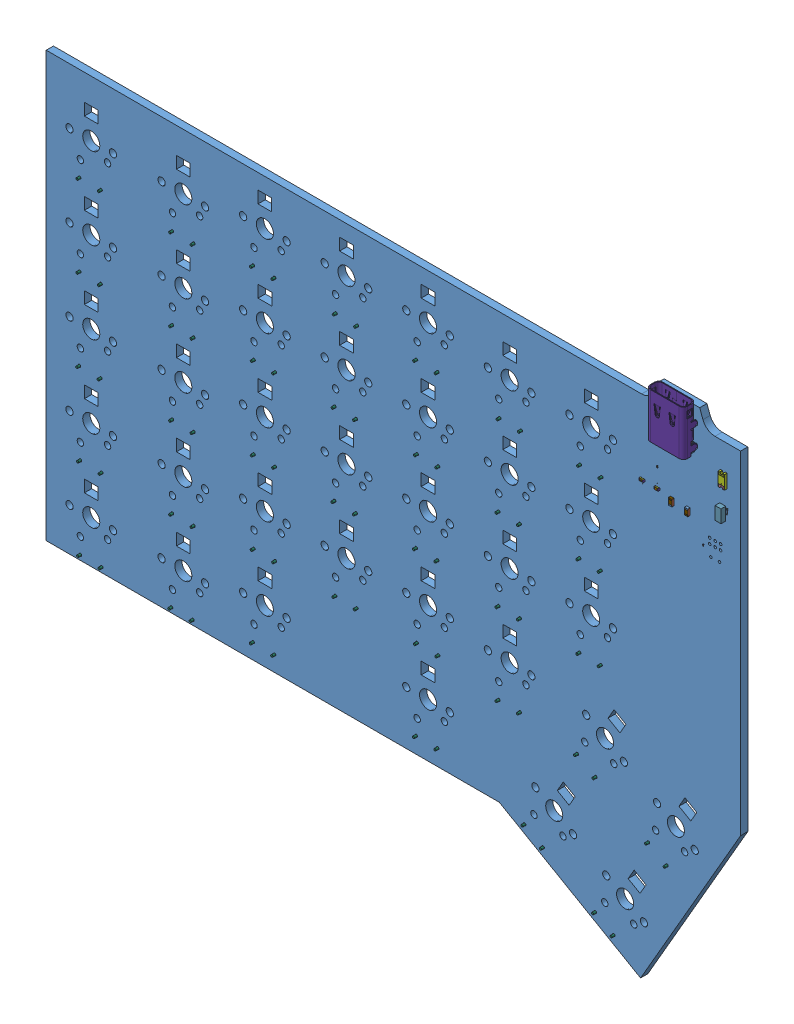
SolidWorks assembly WIRED_PCB, configuration Default. Lengths in mm.
Overall size (162.15 123.21 6.5).
313 component instances, 99 part files, 0 mates.
Components (placement in the parent):
- Board-1: Board [Default] at origin size (162.15 122.24 1.69)
  - Open CASCADE STEP translator 6.8 2.1.1-1: Open CASCADE STEP translator 6.8 2.1.1 [Default] at (0 0 -1.6914) size (162.15 122.24 1.69)
- X1-1: X1 [Default] at origin size (5 3.2 1.05)
  - 5613965808-1: 5613965808 [Default] at (149.15 67.35 -2.7414) size (5 3.2 1.05)
    - Extruded_10-1: Extruded_10 [Default] at origin size (5 3.2 1.05)
- ATmega32U4-1: ATmega32U4 [Default] at origin size (10 10 1.2)
  - 7433191200-1: 7433191200 [Default] at (148.8 79.4 -2.8914) size (10 10 1.2)
    - Extruded_5-1: Extruded_5 [Default] at origin size (10 10 1.2)
- R6-1: R6 [Default] at origin size (1.7 0.95 0.55)
  - 7434017360-1: 7434017360 [Default] at (141 90 -1.6914) x (1 0 0) z (0 0 -1) size (1.7 0.95 0.55)
    - Mid_Body-1: Mid_Body [Default] at (-0.85 -0.475 0) size (1.59 0.95 0.44)
    - Terminal-1: Terminal [Default] at (-0.85 -0.475 0) size (0.1 0.95 0.55)
      - Open_CASCADE_STEP_translator_6.8_1.2.1-1: Open_CASCADE_STEP_translator_6.8_1.2.1 [Default] at origin size (0.1 0.95 0.55)
    - Terminal-2: Terminal [Default] at (0.85 0.475 0) x (-1 0 0) z (0 0 1) size (0.1 0.95 0.55)
      - Open_CASCADE_STEP_translator_6.8_1.2.1-1: Open_CASCADE_STEP_translator_6.8_1.2.1 [Default] at origin size (0.1 0.95 0.55)
    - Mark-1: Mark [Default] at (-0.75 -0.475 0.495) size (1.5 0.95 0.06)
- R5-1: R5 [Default] at origin size (1 1.18 0.41)
  - Res_Vishay_CRCW04021K00FKED_eec-1: Res_Vishay_CRCW04021K00FKED_eec [Default] at (139.2978 111 0) x (-1 0 0) z (0 0 1) size (1 1.18 0.41)
    - body-1: body [Default] at (0 0 0.35) x (1 0 0) z (0 0 -1) size (0.9 0.5 0.3)
    - pad_2-1: pad_2 [Default] at (-0.3133 -0.25 0.4) x (1 0 0) z (0 1 0) size (0.25 0.4 0.5)
    - pad_2-2: pad_2 [Default] at (0.3133 0.25 0.4) x (-1 0 0) z (0 -1 0) size (0.25 0.4 0.5)
    - top-1: top [Default] at (0 0 0.4) x (1 0 0) z (0 0 -1) size (0.61 0.51 0.06)
    - Vishay_3-1: Vishay_3 [Default] at (0.0437 -0.9162 0.4) size (0.15 0.04 0)
    - Vishay_2-1: Vishay_2 [Default] at (0 -0.0009 0.0004) size (0.07 0.06 0)
    - Vishay_7-1: Vishay_7 [Default] at origin size (0.03 0.03 0)
    - Vishay-1: Vishay [Default] at origin size (0.01 0.03 0)
    - Vishay_6-1: Vishay_6 [Default] at origin size (0.03 0.03 0)
    - Vishay_8-1: Vishay_8 [Default] at origin size (0.03 0.03 0)
    - Vishay_5-1: Vishay_5 [Default] at origin size (0.03 0.03 0)
    - Vishay_4-1: Vishay_4 [Default] at origin size (0.03 0.03 0)
- R4-1: R4 [Default] at origin size (1 1.18 0.41)
  - Res_Vishay_CRCW04021K00FKED_eec-1: Res_Vishay_CRCW04021K00FKED_eec [Default] at (142.7978 111 0) size (1 1.18 0.41)
    - body-1: body [Default] at (0 0 0.35) x (1 0 0) z (0 0 -1) size (0.9 0.5 0.3)
    - pad_2-1: pad_2 [Default] at (-0.3133 -0.25 0.4) x (1 0 0) z (0 1 0) size (0.25 0.4 0.5)
    - pad_2-2: pad_2 [Default] at (0.3133 0.25 0.4) x (-1 0 0) z (0 -1 0) size (0.25 0.4 0.5)
    - top-1: top [Default] at (0 0 0.4) x (1 0 0) z (0 0 -1) size (0.61 0.51 0.06)
    - Vishay_3-1: Vishay_3 [Default] at (0.0437 -0.9162 0.4) size (0.15 0.04 0)
    - Vishay_2-1: Vishay_2 [Default] at (0 -0.0009 0.0004) size (0.07 0.06 0)
    - Vishay_7-1: Vishay_7 [Default] at origin size (0.03 0.03 0)
    - Vishay-1: Vishay [Default] at origin size (0.01 0.03 0)
    - Vishay_6-1: Vishay_6 [Default] at origin size (0.03 0.03 0)
    - Vishay_8-1: Vishay_8 [Default] at origin size (0.03 0.03 0)
    - Vishay_5-1: Vishay_5 [Default] at origin size (0.03 0.03 0)
    - Vishay_4-1: Vishay_4 [Default] at origin size (0.03 0.03 0)
- R3-1: R3 [Default] at origin size (3.98 6.22 0.56)
  - Res_TE_Connectivity_CPF0603B2K55E1_eec-1: Res_TE_Connectivity_CPF0603B2K55E1_eec [Default] at (146.25 110.1 0) x (0 -1 0) z (0 0 1) size (6.22 3.98 0.56)
    - 1_2-1: 1_2 [Default] at origin size (0.3 0.8 0.55)
    - 1-1: 1 [Default] at origin size (0.3 0.8 0.55)
    - 2-1: 2 [Default] at origin size (1.45 0.8 0.5)
    - TE_connectivity_Logo_1_11-1: TE_connectivity_Logo_1_11 [Default] at (5.0457 3.7568 0.451) x (-1 0 0) z (0 0 1) size (0.01 0.03 0.1)
    - TE_connectivity_Logo_1_10-1: TE_connectivity_Logo_1_10 [Default] at (0.005 0.0038 0.0005) x (-1 0 0) z (0 0 1) size (0.01 0.03 0.1)
    - TE_connectivity_Logo_1_9-1: TE_connectivity_Logo_1_9 [Default] x (-1 0 0) z (0 0 1) size (0.02 0.02 0.1)
    - TE_connectivity_Logo_1_8-1: TE_connectivity_Logo_1_8 [Default] x (-1 0 0) z (0 0 1) size (0.02 0.02 0.1)
    - TE_connectivity_Logo_1_2-1: TE_connectivity_Logo_1_2 [Default] x (-1 0 0) z (0 0 1) size (0.02 0.02 0.1)
    - TE_connectivity_Logo_1_12-1: TE_connectivity_Logo_1_12 [Default] x (-1 0 0) z (0 0 1) size (0.11 0.12 0.1)
    - TE_connectivity_Logo_1_5-1: TE_connectivity_Logo_1_5 [Default] x (-1 0 0) z (0 0 1) size (0.16 0.04 0.1)
    - TE_connectivity_Logo_1_7-1: TE_connectivity_Logo_1_7 [Default] x (-1 0 0) z (0 0 1) size (0.16 0.04 0.1)
    - TE_connectivity_Logo_1-1: TE_connectivity_Logo_1 [Default] x (-1 0 0) z (0 0 1) size (0.16 0.04 0.1)
    - TE_connectivity_Logo_1_14-1: TE_connectivity_Logo_1_14 [Default] x (-1 0 0) z (0 0 1) size (0.1 0.12 0.1)
    - TE_connectivity_Logo_1_6-1: TE_connectivity_Logo_1_6 [Default] x (-1 0 0) z (0 0 1) size (0.02 0.03 0.1)
    - TE_connectivity_Logo_1_3-1: TE_connectivity_Logo_1_3 [Default] x (-1 0 0) z (0 0 1) size (0.02 0.02 0.1)
    - TE_connectivity_Logo_1_13-1: TE_connectivity_Logo_1_13 [Default] x (-1 0 0) z (0 0 1) size (0.02 0.02 0.11)
    - TE_connectivity_Logo_1_4-1: TE_connectivity_Logo_1_4 [Default] x (-1 0 0) z (0 0 1) size (0.02 0.02 0.1)
    - TE_connectivity_Logo_1_15-1: TE_connectivity_Logo_1_15 [Default] x (-1 0 0) z (0 0 1) size (0.02 0.03 0.1)
    - 3-1: 3 [Default] at origin size (0.95 0.8 0.05)
- R2-1: R2 [Default] at origin size (3.98 6.22 0.56)
  - Res_TE_Connectivity_CPF0603B2K55E1_eec-1: Res_TE_Connectivity_CPF0603B2K55E1_eec [Default] at (150 110 0) x (0 1 0) z (0 0 1) size (6.22 3.98 0.56)
    - 1_2-1: 1_2 [Default] at origin size (0.3 0.8 0.55)
    - 1-1: 1 [Default] at origin size (0.3 0.8 0.55)
    - 2-1: 2 [Default] at origin size (1.45 0.8 0.5)
    - TE_connectivity_Logo_1_11-1: TE_connectivity_Logo_1_11 [Default] at (5.0457 3.7568 0.451) x (-1 0 0) z (0 0 1) size (0.01 0.03 0.1)
    - TE_connectivity_Logo_1_10-1: TE_connectivity_Logo_1_10 [Default] at (0.005 0.0038 0.0005) x (-1 0 0) z (0 0 1) size (0.01 0.03 0.1)
    - TE_connectivity_Logo_1_9-1: TE_connectivity_Logo_1_9 [Default] x (-1 0 0) z (0 0 1) size (0.02 0.02 0.1)
    - TE_connectivity_Logo_1_8-1: TE_connectivity_Logo_1_8 [Default] x (-1 0 0) z (0 0 1) size (0.02 0.02 0.1)
    - TE_connectivity_Logo_1_2-1: TE_connectivity_Logo_1_2 [Default] x (-1 0 0) z (0 0 1) size (0.02 0.02 0.1)
    - TE_connectivity_Logo_1_12-1: TE_connectivity_Logo_1_12 [Default] x (-1 0 0) z (0 0 1) size (0.11 0.12 0.1)
    - TE_connectivity_Logo_1_5-1: TE_connectivity_Logo_1_5 [Default] x (-1 0 0) z (0 0 1) size (0.16 0.04 0.1)
    - TE_connectivity_Logo_1_7-1: TE_connectivity_Logo_1_7 [Default] x (-1 0 0) z (0 0 1) size (0.16 0.04 0.1)
    - TE_connectivity_Logo_1-1: TE_connectivity_Logo_1 [Default] x (-1 0 0) z (0 0 1) size (0.16 0.04 0.1)
    - TE_connectivity_Logo_1_14-1: TE_connectivity_Logo_1_14 [Default] x (-1 0 0) z (0 0 1) size (0.1 0.12 0.1)
    - TE_connectivity_Logo_1_6-1: TE_connectivity_Logo_1_6 [Default] x (-1 0 0) z (0 0 1) size (0.02 0.03 0.1)
    - TE_connectivity_Logo_1_3-1: TE_connectivity_Logo_1_3 [Default] x (-1 0 0) z (0 0 1) size (0.02 0.02 0.1)
    - TE_connectivity_Logo_1_13-1: TE_connectivity_Logo_1_13 [Default] x (-1 0 0) z (0 0 1) size (0.02 0.02 0.11)
    - TE_connectivity_Logo_1_4-1: TE_connectivity_Logo_1_4 [Default] x (-1 0 0) z (0 0 1) size (0.02 0.02 0.1)
    - TE_connectivity_Logo_1_15-1: TE_connectivity_Logo_1_15 [Default] x (-1 0 0) z (0 0 1) size (0.02 0.03 0.1)
    - 3-1: 3 [Default] at origin size (0.95 0.8 0.05)
- R1-1: R1 [Default] at origin size (1.66 3.2 0.66)
  - Res_Vishay_MCA12060D1541BP100_eec-1: Res_Vishay_MCA12060D1541BP100_eec [Default] at (159.25 66 -1.6914) x (0 -1 0) z (0 0 -1) size (3.2 1.66 0.66)
    - body_3-1: body_3 [Default] at (0 0 0.6) x (1 0 0) z (0 0 -1) size (3.1 1.6 0.55)
    - pad-1: pad [Default] at (-1.4133 -0.8 0.65) x (1 0 0) z (0 1 0) size (0.5 0.65 1.6)
    - pad-2: pad [Default] at (1.4133 0.8 0.65) x (-1 0 0) z (0 -1 0) size (0.5 0.65 1.6)
    - top_2-1: top_2 [Default] at (0 0 0.65) x (1 0 0) z (0 0 -1) size (2.2 1.6 0.05)
    - Vishay_15-1: Vishay_15 [Default] at (0.0405 -0.7888 0.65) size (0.45 0.11 0.01)
    - Vishay_14-1: Vishay_14 [Default] at (0 -0.0008 0.0006) size (0.21 0.18 0.01)
    - Vishay_11-1: Vishay_11 [Default] at origin size (0.09 0.09 0.01)
    - Vishay_9-1: Vishay_9 [Default] at origin size (0.03 0.08 0.01)
    - Vishay_13-1: Vishay_13 [Default] at origin size (0.08 0.09 0.01)
    - Vishay_16-1: Vishay_16 [Default] at origin size (0.08 0.08 0.01)
    - Vishay_10-1: Vishay_10 [Default] at origin size (0.1 0.09 0.01)
    - Vishay_12-1: Vishay_12 [Default] at origin size (0.09 0.08 0.01)
    - bottom-1: bottom [Default] at (0 0 0.05) x (1 0 0) z (0 0 -1) size (2.2 1.6 0.05)
- J1-1: J1 [Default] at origin size (8.74 11.79 4.86)
  - 632723300011-1: 632723300011 [Default] at (147.4999 128.2749 1.57) x (1 0 0) z (0 1 0) size (8.74 4.86 11.79)
    - 632723300011_Housing-1: 632723300011_Housing [Default] at origin size (8.34 2.56 8.2)
    - 632723300011_Shielding_3_v3-1: 632723300011_Shielding_3_v3 [Default] at (0 0.05 0) size (7.5 3.43 8.64)
    - 632723300011_PIN2_Top_v3-1: 632723300011_PIN2_Top_v3 [Default] at (0.75 2.37 -6.335) x (0 0 1) z (0 -1 0) size (9.09 0.28 1.93)
    - 632723300011_Housing_TOP-1: 632723300011_Housing_TOP [Default] at (0 -0.6 -3.9) x (1 0 0) z (0 -1 0) size (6.7 3.25 1.23)
    - 632723300011_PIN2_Top_v3-2: 632723300011_PIN2_Top_v3 [Default] at (1.75 2.37 -6.335) x (0 0 1) z (0 -1 0) size (9.09 0.28 1.93)
    - 632723300011_PIN2_Top_v3-3: 632723300011_PIN2_Top_v3 [Default] at (2.25 2.37 -6.335) x (0 0 1) z (0 -1 0) size (9.09 0.28 1.93)
    - 632723300011_Shielding_1_v3-1: 632723300011_Shielding_1_v3 [Default] at (0 0 -0.475) x (-1 0 0) z (0 -1 0) size (8.74 10.6 4.86)
    - 632723300011_PIN1_Top_v3-1: 632723300011_PIN1_Top_v3 [Default] at (2.75 1.97 -6.335) x (0 0 1) z (0 -1 0) size (9.59 0.28 1.93)
    - 632723300011_PIN2_Top_v3-4: 632723300011_PIN2_Top_v3 [Default] at (-0.75 2.37 -6.335) x (0 0 1) z (0 -1 0) size (9.09 0.28 1.93)
    - 632723300011_PIN2_Top_v3-5: 632723300011_PIN2_Top_v3 [Default] at (-0.25 2.37 -6.335) x (0 0 1) z (0 -1 0) size (9.09 0.28 1.93)
    - 632723300011_PIN2_Top_v3-6: 632723300011_PIN2_Top_v3 [Default] at (-2.25 2.37 -6.335) x (0 0 1) z (0 -1 0) size (9.09 0.28 1.93)
    - 632723300011_PIN1_Top_v3-2: 632723300011_PIN1_Top_v3 [Default] at (-1.25 1.97 -6.335) x (0 0 1) z (0 -1 0) size (9.59 0.28 1.93)
    - 632723300011_PIN1_Top_v3-3: 632723300011_PIN1_Top_v3 [Default] at (-2.75 1.97 -6.335) x (0 0 1) z (0 -1 0) size (9.59 0.28 1.93)
    - 632723300011_PIN2_Top_v3-7: 632723300011_PIN2_Top_v3 [Default] at (-1.75 2.37 -6.335) x (0 0 1) z (0 -1 0) size (9.09 0.28 1.93)
    - 632723300011_Housing_Bottom-1: 632723300011_Housing_Bottom [Default] at (0 0.89 -5.285) x (-1 0 0) z (0 -1 0) size (8.34 5.47 2.38)
    - 632723300011_PIN1_Bottom_v3-1: 632723300011_PIN1_Bottom_v3 [Default] at (-2.8 3.3765 -5.46) x (1 0 0) z (0 -1 0) size (0.39 8.16 3.22)
    - 632723300011_PIN1_Top_v3-4: 632723300011_PIN1_Top_v3 [Default] at (1.25 1.97 -6.335) x (0 0 1) z (0 -1 0) size (9.59 0.28 1.93)
    - 632723300011_PIN2_Bottom_v3-1: 632723300011_PIN2_Bottom_v3 [Default] at (-2.4 3.3765 -4.75) x (1 0 0) z (0 -1 0) size (0.6 6.95 3.27)
    - 632723300011_PIN4_Bottom_v3-1: 632723300011_PIN4_Bottom_v3 [Default] at (-1.6 3.3765 -4.7565) x (1 0 0) z (0 -1 0) size (0.54 6.96 3.22)
    - 632723300011_PIN5_Bottom_v3-1: 632723300011_PIN5_Bottom_v3 [Default] at (-1.2 3.3765 -5.46) x (1 0 0) z (0 -1 0) size (0.41 8.16 3.22)
    - 632723300011_PIN6_Bottom_v3-1: 632723300011_PIN6_Bottom_v3 [Default] at (-0.8 3.3765 -4.76) x (1 0 0) z (0 -1 0) size (0.39 6.96 3.22)
    - 632723300011_PIN7_Bottom_v3-1: 632723300011_PIN7_Bottom_v3 [Default] at (-0.4 3.3765 -5.46) x (1 0 0) z (0 -1 0) size (0.6 7.66 3.27)
    - 632723300011_PIN2_Top_v3-8: 632723300011_PIN2_Top_v3 [Default] at (0.25 2.37 -6.335) x (0 0 1) z (0 -1 0) size (9.09 0.28 1.93)
    - 632723300011_Shielding_2-1: 632723300011_Shielding_2 [Default] at (0 -0.8 -1.425) x (0 0 1) z (0 -1 0) size (2.92 7.5 1.07)
    - 632723300011_PIN1_Bottom_v3_mir-1: 632723300011_PIN1_Bottom_v3_mir [Default] at (2.8 3.3765 -5.46) x (-1 0 0) z (0 -1 0) size (0.39 8.16 3.22)
    - 632723300011_PIN4_Bottom_v3_mir-1: 632723300011_PIN4_Bottom_v3_mir [Default] at (1.6 3.3765 -4.7565) x (-1 0 0) z (0 -1 0) size (0.55 6.96 3.22)
    - 632723300011_PIN6_Bottom_v3_mir-1: 632723300011_PIN6_Bottom_v3_mir [Default] at (0.8 3.3765 -4.76) x (-1 0 0) z (0 -1 0) size (0.39 6.96 3.22)
    - 632723300011_PIN2_Bottom_v3_mir-1: 632723300011_PIN2_Bottom_v3_mir [Default] at (2.4 3.3765 -4.75) x (-1 0 0) z (0 -1 0) size (0.6 6.95 3.27)
    - 632723300011_PIN5_Bottom_v3_mir-1: 632723300011_PIN5_Bottom_v3_mir [Default] at (1.2 3.3765 -5.46) x (-1 0 0) z (0 -1 0) size (0.41 8.16 3.22)
    - 632723300011_PIN7_Bottom_v3_mir-1: 632723300011_PIN7_Bottom_v3_mir [Default] at (0.4 3.3765 -5.46) x (-1 0 0) z (0 -1 0) size (0.6 7.66 3.27)
    - 632723300011_Housing_Bottom3-1: 632723300011_Housing_Bottom3 [Default] at (0 0.89 -5.284) x (-1 0 0) z (0 -1 0) size (6.46 2.1 0.78)
    - 632723300011_Shielding_2-2: 632723300011_Shielding_2 [Default] at (0 0.75 -1.425) x (0 0 1) z (0 1 0) size (2.92 7.5 1.07)
- F1-1: F1 [Default] at origin size (1.77 8.5 0.59)
  - Fuse_Littelfuse_0468_500NR_eec-1: Fuse_Littelfuse_0468_500NR_eec [Default] at (158.25 120.5 0) x (0 -1 0) z (0 0 1) size (8.5 1.77 0.59)
    - Lead-1: Lead [Default] at (-1.2623 0.0004 0) size (0.66 1.52 0.59)
    - Littelfuse_9-1: Littelfuse_9 [Default] at (-6.2822 -0.8078 0.5757) size (0.13 0.19 0)
    - Littelfuse_6-1: Littelfuse_6 [Default] at (-0.0063 -0.0008 0.0006) size (0.13 0.19 0.01)
    - Littelfuse_14-1: Littelfuse_14 [Default] at origin size (0.06 0.23 0)
    - Littelfuse_4-1: Littelfuse_4 [Default] at origin size (0.13 0.19 0)
    - Littelfuse-1: Littelfuse [Default] at origin size (0.09 0.21 0)
    - Littelfuse_12-1: Littelfuse_12 [Default] at origin size (0.06 0.19 0)
    - Littelfuse_7-1: Littelfuse_7 [Default] at origin size (0.36 0.29 0.01)
    - Littelfuse_3-1: Littelfuse_3 [Default] at origin size (0.1 0.17 0.01)
    - Littelfuse_5-1: Littelfuse_5 [Default] at origin size (0.36 0.16 0.01)
    - Littelfuse_11-1: Littelfuse_11 [Default] at origin size (0.1 0.23 0)
    - Littelfuse_8-1: Littelfuse_8 [Default] at origin size (0.06 0.03 0)
    - Littelfuse_10-1: Littelfuse_10 [Default] at origin size (0.09 0.21 0)
    - Littelfuse_13-1: Littelfuse_13 [Default] at origin size (0.08 0.23 0)
    - Littelfuse_2-1: Littelfuse_2 [Default] at origin size (0.13 0.19 0.01)
    - body-1: body [Default] at (0 0 0.003) size (0.9 0.5 0.3)
    - Lead_MIR2-1: Lead_MIR2 [Default] at (1.2623 0.0004 0) x (-1 0 0) z (0 0 -1) size (0.66 1.52 0.59)
- D36-1: D36 [Default] at origin size (1.4 3 1.1)
  - 5613955808-1: 5613955808 [Default] at (158 113.75 0) size (1.4 3 1.1)
    - Extruded_11-1: Extruded_11 [Default] at origin size (1.4 3 1.1)
- D35-1: D35 [Default] at origin size (5.51 4.05 4.1)
  - User_Library-1N4148_x5mm-1: User_Library-1N4148_x5mm [Default] at (142.8 36.9999 -2.7041) x (0.866025 -0.5 0) z (0 0 -1) size (5.5 1.5 4.1)
- D34-1: D34 [Default] at origin size (5.51 4.05 4.1)
  - User_Library-1N4148_x5mm-1: User_Library-1N4148_x5mm [Default] at (130.4 16.6999 -2.7041) x (0.866025 -0.5 0) z (0 0 -1) size (5.5 1.5 4.1)
- D33-1: D33 [Default] at origin size (5.51 4.05 4.1)
  - User_Library-1N4148_x5mm-1: User_Library-1N4148_x5mm [Default] at (113.9 26.1999 -2.7041) x (0.866025 -0.5 0) z (0 0 -1) size (5.5 1.5 4.1)
- D32-1: D32 [Default] at origin size (5.5 1.5 4.1)
  - User_Library-1N4148_x5mm-1: User_Library-1N4148_x5mm [Default] at (88.9349 32.6999 -2.7041) x (1 0 0) z (0 0 -1) size (5.5 1.5 4.1)
- D31-1: D31 [Default] at origin size (5.5 1.5 4.1)
  - User_Library-1N4148_x5mm-1: User_Library-1N4148_x5mm [Default] at (50.8349 32.5999 -2.7041) x (1 0 0) z (0 0 -1) size (5.5 1.5 4.1)
- D30-1: D30 [Default] at origin size (5.5 1.5 4.1)
  - User_Library-1N4148_x5mm-1: User_Library-1N4148_x5mm [Default] at (31.7849 30.0999 -2.7041) x (1 0 0) z (0 0 -1) size (5.5 1.5 4.1)
- D29-1: D29 [Default] at origin size (5.5 1.5 4.1)
  - User_Library-1N4148_x5mm-1: User_Library-1N4148_x5mm [Default] at (10.4949 30.0999 -2.7041) x (1 0 0) z (0 0 -1) size (5.5 1.5 4.1)
- D28-1: D28 [Default] at origin size (5.51 4.05 4.1)
  - User_Library-1N4148_x5mm-1: User_Library-1N4148_x5mm [Default] at (126.2 46.5999 -2.7041) x (0.866025 -0.5 0) z (0 0 -1) size (5.5 1.5 4.1)
- D27-1: D27 [Default] at origin size (5.5 1.5 4.1)
  - User_Library-1N4148_x5mm-1: User_Library-1N4148_x5mm [Default] at (108.2001 49.5999 -2.7041) x (1 0 0) z (0 0 -1) size (5.5 1.5 4.1)
- D26-1: D26 [Default] at origin size (5.5 1.5 4.1)
  - User_Library-1N4148_x5mm-1: User_Library-1N4148_x5mm [Default] at (89.1449 51.5999 -2.7041) x (1 0 0) z (0 0 -1) size (5.5 1.5 4.1)
- D25-1: D25 [Default] at origin size (5.5 1.5 4.1)
  - User_Library-1N4148_x5mm-1: User_Library-1N4148_x5mm [Default] at (70.0949 51.5999 -2.7041) x (1 0 0) z (0 0 -1) size (5.5 1.5 4.1)
- D24-1: D24 [Default] at origin size (5.5 1.5 4.1)
  - User_Library-1N4148_x5mm-1: User_Library-1N4148_x5mm [Default] at (51.0428 51.5999 -2.7041) x (1 0 0) z (0 0 -1) size (5.5 1.5 4.1)
- D23-1: D23 [Default] at origin size (5.5 1.5 4.1)
  - User_Library-1N4148_x5mm-1: User_Library-1N4148_x5mm [Default] at (31.9949 49.1999 -2.7041) x (1 0 0) z (0 0 -1) size (5.5 1.5 4.1)
- D22-1: D22 [Default] at origin size (5.5 1.5 4.1)
  - User_Library-1N4148_x5mm-1: User_Library-1N4148_x5mm [Default] at (10.4949 49.1999 -2.7041) x (1 0 0) z (0 0 -1) size (5.5 1.5 4.1)
- D21-1: D21 [Default] at origin size (5.5 1.5 4.1)
  - User_Library-1N4148_x5mm-1: User_Library-1N4148_x5mm [Default] at (127.0828 68.5999 -2.7041) x (1 0 0) z (0 0 -1) size (5.5 1.5 4.1)
- D20-1: D20 [Default] at origin size (5.5 1.5 4.1)
  - User_Library-1N4148_x5mm-1: User_Library-1N4148_x5mm [Default] at (108.2001 68.5999 -2.7041) x (1 0 0) z (0 0 -1) size (5.5 1.5 4.1)
- D19-1: D19 [Default] at origin size (5.5 1.5 4.1)
  - User_Library-1N4148_x5mm-1: User_Library-1N4148_x5mm [Default] at (88.9349 70.6999 -2.7041) x (1 0 0) z (0 0 -1) size (5.5 1.5 4.1)
- D18-1: D18 [Default] at origin size (5.5 1.5 4.1)
  - User_Library-1N4148_x5mm-1: User_Library-1N4148_x5mm [Default] at (69.8849 70.6999 -2.7041) x (1 0 0) z (0 0 -1) size (5.5 1.5 4.1)
- D17-1: D17 [Default] at origin size (5.5 1.5 4.1)
  - User_Library-1N4148_x5mm-1: User_Library-1N4148_x5mm [Default] at (51.0428 70.6999 -2.7041) x (1 0 0) z (0 0 -1) size (5.5 1.5 4.1)
- D16-1: D16 [Default] at origin size (5.5 1.5 4.1)
  - User_Library-1N4148_x5mm-1: User_Library-1N4148_x5mm [Default] at (31.9949 68.1999 -2.7041) x (1 0 0) z (0 0 -1) size (5.5 1.5 4.1)
- D15-1: D15 [Default] at origin size (5.5 1.5 4.1)
  - User_Library-1N4148_x5mm-1: User_Library-1N4148_x5mm [Default] at (10.2849 68.1999 -2.7041) x (1 0 0) z (0 0 -1) size (5.5 1.5 4.1)
- D14-1: D14 [Default] at origin size (5.5 1.5 4.1)
  - User_Library-1N4148_x5mm-1: User_Library-1N4148_x5mm [Default] at (127.0828 87.6999 -2.7041) x (1 0 0) z (0 0 -1) size (5.5 1.5 4.1)
- D13-1: D13 [Default] at origin size (5.5 1.5 4.1)
  - User_Library-1N4148_x5mm-1: User_Library-1N4148_x5mm [Default] at (108.2001 87.6999 -2.7041) x (1 0 0) z (0 0 -1) size (5.5 1.5 4.1)
- D12-1: D12 [Default] at origin size (5.5 1.5 4.1)
  - User_Library-1N4148_x5mm-1: User_Library-1N4148_x5mm [Default] at (89.1428 89.7999 -2.7041) x (1 0 0) z (0 0 -1) size (5.5 1.5 4.1)
- D11-1: D11 [Default] at origin size (5.5 1.5 4.1)
  - User_Library-1N4148_x5mm-1: User_Library-1N4148_x5mm [Default] at (69.9349 89.7999 -2.7041) x (1 0 0) z (0 0 -1) size (5.5 1.5 4.1)
- D10-1: D10 [Default] at origin size (5.5 1.5 4.1)
  - User_Library-1N4148_x5mm-1: User_Library-1N4148_x5mm [Default] at (51.0428 89.7999 -2.7041) x (1 0 0) z (0 0 -1) size (5.5 1.5 4.1)
- D9-1: D9 [Default] at origin size (5.5 1.5 4.1)
  - User_Library-1N4148_x5mm-1: User_Library-1N4148_x5mm [Default] at (31.9949 87.2999 -2.7041) x (1 0 0) z (0 0 -1) size (5.5 1.5 4.1)
- D8-1: D8 [Default] at origin size (5.5 1.5 4.1)
  - User_Library-1N4148_x5mm-1: User_Library-1N4148_x5mm [Default] at (10.3349 87.2999 -2.7041) x (1 0 0) z (0 0 -1) size (5.5 1.5 4.1)
- D7-1: D7 [Default] at origin size (5.5 1.5 4.1)
  - User_Library-1N4148_x5mm-1: User_Library-1N4148_x5mm [Default] at (127.2428 106.6999 -2.7041) x (1 0 0) z (0 0 -1) size (5.5 1.5 4.1)
- D6-1: D6 [Default] at origin size (5.5 1.5 4.1)
  - User_Library-1N4148_x5mm-1: User_Library-1N4148_x5mm [Default] at (108.4328 106.6999 -2.7041) x (1 0 0) z (0 0 -1) size (5.5 1.5 4.1)
- D5-1: D5 [Default] at origin size (5.5 1.5 4.1)
  - User_Library-1N4148_x5mm-1: User_Library-1N4148_x5mm [Default] at (88.9828 108.7999 -2.7041) x (1 0 0) z (0 0 -1) size (5.5 1.5 4.1)
- D4-1: D4 [Default] at origin size (5.5 1.5 4.1)
  - User_Library-1N4148_x5mm-1: User_Library-1N4148_x5mm [Default] at (70.2001 108.7999 -2.7041) x (1 0 0) z (0 0 -1) size (5.5 1.5 4.1)
- D3-1: D3 [Default] at origin size (5.5 1.5 4.1)
  - User_Library-1N4148_x5mm-1: User_Library-1N4148_x5mm [Default] at (50.8828 108.7999 -2.7041) x (1 0 0) z (0 0 -1) size (5.5 1.5 4.1)
- D2-1: D2 [Default] at origin size (5.5 1.5 4.1)
  - User_Library-1N4148_x5mm-1: User_Library-1N4148_x5mm [Default] at (31.9928 106.2999 -2.7041) x (1 0 0) z (0 0 -1) size (5.5 1.5 4.1)
- D1-1: D1 [Default] at origin size (5.5 1.5 4.1)
  - User_Library-1N4148_x5mm-1: User_Library-1N4148_x5mm [Default] at (10.3328 106.2999 -2.7041) x (1 0 0) z (0 0 -1) size (5.5 1.5 4.1)
- C13-1: C13 [Default] at origin size (0.51 1.01 0.56)
  - Cap_Kemet_C0402C562J5RACTU_eec-1: Cap_Kemet_C0402C562J5RACTU_eec [Default] at (152.5 90 -1.6914) x (0 -1 0) z (0 0 -1) size (1.01 0.51 0.56)
    - body_2-1: body_2 [Default] at origin size (0.4 0.5 0.55)
    - terminals-1: terminals [Default] at origin size (0.31 0.51 0.56)
    - terminals_2-1: terminals_2 [Default] at origin size (0.31 0.51 0.56)
    - value-1: value [Default] at (0 0 0.55) size (0.37 0.29 0.15)
- C12-1: C12 [Default] at origin size (0.51 1.01 0.56)
  - Cap_Kemet_C0402C562J5RACTU_eec-1: Cap_Kemet_C0402C562J5RACTU_eec [Default] at (150.75 90 -1.6914) x (0 -1 0) z (0 0 -1) size (1.01 0.51 0.56)
    - body_2-1: body_2 [Default] at origin size (0.4 0.5 0.55)
    - terminals-1: terminals [Default] at origin size (0.31 0.51 0.56)
    - terminals_2-1: terminals_2 [Default] at origin size (0.31 0.51 0.56)
    - value-1: value [Default] at (0 0 0.55) size (0.37 0.29 0.15)
- C11-1: C11 [Default] at origin size (0.51 1.01 0.56)
  - Cap_Kemet_C0402C562J5RACTU_eec-1: Cap_Kemet_C0402C562J5RACTU_eec [Default] at (149 90 -1.6914) x (0 -1 0) z (0 0 -1) size (1.01 0.51 0.56)
    - body_2-1: body_2 [Default] at origin size (0.4 0.5 0.55)
    - terminals-1: terminals [Default] at origin size (0.31 0.51 0.56)
    - terminals_2-1: terminals_2 [Default] at origin size (0.31 0.51 0.56)
    - value-1: value [Default] at (0 0 0.55) size (0.37 0.29 0.15)
- C10-1: C10 [Default] at origin size (0.51 1.01 0.56)
  - Cap_Kemet_C0402C562J5RACTU_eec-1: Cap_Kemet_C0402C562J5RACTU_eec [Default] at (147.25 90 -1.6914) x (0 -1 0) z (0 0 -1) size (1.01 0.51 0.56)
    - body_2-1: body_2 [Default] at origin size (0.4 0.5 0.55)
    - terminals-1: terminals [Default] at origin size (0.31 0.51 0.56)
    - terminals_2-1: terminals_2 [Default] at origin size (0.31 0.51 0.56)
    - value-1: value [Default] at (0 0 0.55) size (0.37 0.29 0.15)
- C9-1: C9 [Default] at origin size (0.51 1.01 0.56)
  - Cap_Kemet_C0402C562J5RACTU_eec-1: Cap_Kemet_C0402C562J5RACTU_eec [Default] at (145.5 90 -1.6914) x (0 -1 0) z (0 0 -1) size (1.01 0.51 0.56)
    - body_2-1: body_2 [Default] at origin size (0.4 0.5 0.55)
    - terminals-1: terminals [Default] at origin size (0.31 0.51 0.56)
    - terminals_2-1: terminals_2 [Default] at origin size (0.31 0.51 0.56)
    - value-1: value [Default] at (0 0 0.55) size (0.37 0.29 0.15)
- C8-1: C8 [Default] at origin size (1.8 3.4 1.3)
  - 8284095360-1: 8284095360 [Default] at (159 75.95 -2.9914) size (1.8 0.5 1.3)
    - Extruded_3-1: Extruded_3 [Default] at origin size (1.8 0.5 1.3)
  - 8284095360-2: 8284095360 [Default] at (159 73.05 -2.9914) size (1.8 0.5 1.3)
    - Extruded_3-1: Extruded_3 [Default] at origin size (1.8 0.5 1.3)
  - 8284081680-1: 8284081680 [Default] at (159 74.5 -2.9914) size (1.8 2.4 1.3)
    - Extruded_6-1: Extruded_6 [Default] at origin size (1.8 2.4 1.3)
- C7-1: C7 [Default] at origin size (0.6 1.1 0.56)
  - 5613967728-1: 5613967728 [Default] at (144.25 66.25 -2.2514) size (0.6 0.6 0.56)
    - Extruded-1: Extruded [Default] at origin size (0.6 0.6 0.56)
  - 8144647408-1: 8144647408 [Default] at (144.25 66.675 -2.2514) size (0.6 0.25 0.56)
    - Extruded_7-1: Extruded_7 [Default] at origin size (0.6 0.25 0.56)
  - 8144647408-2: 8144647408 [Default] at (144.25 65.825 -2.2514) size (0.6 0.25 0.56)
    - Extruded_7-1: Extruded_7 [Default] at origin size (0.6 0.25 0.56)
- C6-1: C6 [Default] at origin size (0.6 1.1 0.56)
  - 5613967728-1: 5613967728 [Default] at (154 66.44 -2.2514) size (0.6 0.6 0.56)
    - Extruded-1: Extruded [Default] at origin size (0.6 0.6 0.56)
  - 8144647408-1: 8144647408 [Default] at (154 66.015 -2.2514) size (0.6 0.25 0.56)
    - Extruded_7-1: Extruded_7 [Default] at origin size (0.6 0.25 0.56)
  - 8144647408-2: 8144647408 [Default] at (154 66.865 -2.2514) size (0.6 0.25 0.56)
    - Extruded_7-1: Extruded_7 [Default] at origin size (0.6 0.25 0.56)
- C5-1: C5 [Default] at origin size (1.7 0.9 0.9)
  - 5613968128-1: 5613968128 [Default] at (157.225 52 -2.5914) size (1 0.9 0.9)
    - Extruded_4-1: Extruded_4 [Default] at origin size (1 0.9 0.9)
  - 5613964048-1: 5613964048 [Default] at (157.9 52 -2.5914) size (0.35 0.9 0.9)
    - Extruded_9-1: Extruded_9 [Default] at origin size (0.35 0.9 0.9)
  - 5613964048-2: 5613964048 [Default] at (156.55 52 -2.5914) size (0.35 0.9 0.9)
    - Extruded_9-1: Extruded_9 [Default] at origin size (0.35 0.9 0.9)
- C4-1: C4 [Default] at origin size (0.9 1.7 0.9)
  - 5613956208-1: 5613956208 [Default] at (136.3 65.975 -2.5914) size (0.9 1 0.9)
    - Extruded_2-1: Extruded_2 [Default] at origin size (0.9 1 0.9)
  - 5613953728-1: 5613953728 [Default] at (136.3 65.3 -2.5914) size (0.9 0.35 0.9)
    - Extruded_8-1: Extruded_8 [Default] at origin size (0.9 0.35 0.9)
  - 5613953728-2: 5613953728 [Default] at (136.3 66.65 -2.5914) size (0.9 0.35 0.9)
    - Extruded_8-1: Extruded_8 [Default] at origin size (0.9 0.35 0.9)
- C3-1: C3 [Default] at origin size (0.9 1.7 0.9)
  - 5613956208-1: 5613956208 [Default] at (136.5 83.8 -2.5914) size (0.9 1 0.9)
    - Extruded_2-1: Extruded_2 [Default] at origin size (0.9 1 0.9)
  - 5613953728-1: 5613953728 [Default] at (136.5 83.125 -2.5914) size (0.9 0.35 0.9)
    - Extruded_8-1: Extruded_8 [Default] at origin size (0.9 0.35 0.9)
  - 5613953728-2: 5613953728 [Default] at (136.5 84.475 -2.5914) size (0.9 0.35 0.9)
    - Extruded_8-1: Extruded_8 [Default] at origin size (0.9 0.35 0.9)
- C2-1: C2 [Default] at origin size (0.9 1.7 0.9)
  - 5613956208-1: 5613956208 [Default] at (136.5 102.9 -2.5914) size (0.9 1 0.9)
    - Extruded_2-1: Extruded_2 [Default] at origin size (0.9 1 0.9)
  - 5613953728-1: 5613953728 [Default] at (136.5 102.225 -2.5914) size (0.9 0.35 0.9)
    - Extruded_8-1: Extruded_8 [Default] at origin size (0.9 0.35 0.9)
  - 5613953728-2: 5613953728 [Default] at (136.5 103.575 -2.5914) size (0.9 0.35 0.9)
    - Extruded_8-1: Extruded_8 [Default] at origin size (0.9 0.35 0.9)
- C1-1: C1 [Default] at origin size (0.9 1.7 0.9)
  - 5613956208-1: 5613956208 [Default] at (136.4 121.825 -2.5914) size (0.9 1 0.9)
    - Extruded_2-1: Extruded_2 [Default] at origin size (0.9 1 0.9)
  - 5613953728-1: 5613953728 [Default] at (136.4 122.5 -2.5914) size (0.9 0.35 0.9)
    - Extruded_8-1: Extruded_8 [Default] at origin size (0.9 0.35 0.9)
  - 5613953728-2: 5613953728 [Default] at (136.4 121.15 -2.5914) size (0.9 0.35 0.9)
    - Extruded_8-1: Extruded_8 [Default] at origin size (0.9 0.35 0.9)
